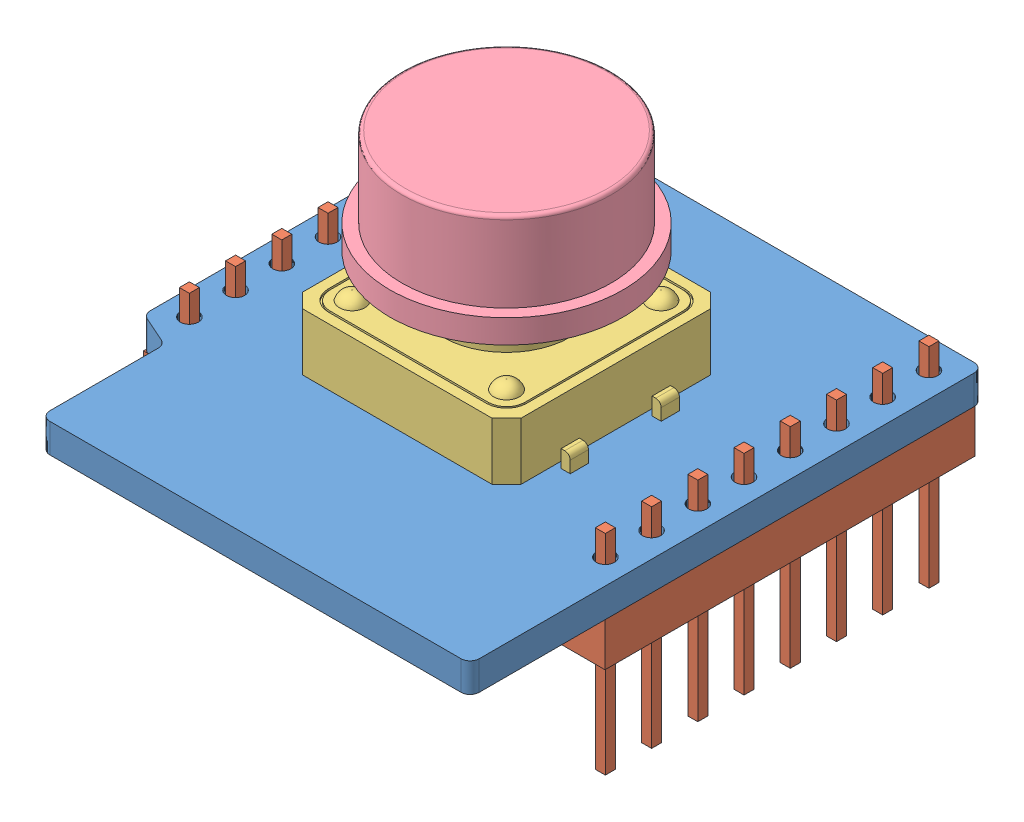
SolidWorks assembly LOLIN 1-button shield, configuration Default. Lengths in mm.
Overall size (25.6 21.7 28.2).
5 component instances, 4 part files, 12 mates.
Components (placement in the parent):
- LOLIN template-1: LOLIN template [Default] at origin size (25.6 1.6 28.2)
- header_m8-1: header_m8 [Default] at (-11.43 -2.5 -27.85) x (0 0 1) z (-1 0 0) size (20.32 11.5 2.5)
- header_m8-2: header_m8 [Default] at (11.43 -2.5 -27.85) x (0 0 1) z (-1 0 0) size (20.32 11.5 2.5)
- Tactile Push Button B3F-405 12X12x7.3mm-1: Tactile Push Button B3F-405 12X12x7.3mm [По умолчанию] at (0 1.95 -14.8) size (13 10.05 12)
- Tactile Button Caps for B3F-4055 12X12X7.3MM - Blue-1: Tactile Button Caps for B3F-4055 12X12X7.3MM - Blue [По умолчанию] at (0 13.2 -14.8) x (-1 0 0) z (0 0 1) size (12.8 7.6 12.8)
Mates (geometry in assembly coordinates):
- Coincident10: coincident anti-aligned: plane of LOLIN template-1 through (0 0 0) normal (0 -1 0); plane of header_m8-1 through (-12.68 0 -27.85) normal (0 1 0)
- Coincident3: coincident anti-aligned: plane of breakout_template-1 through (0 0 0) normal (0 -1 0); plane of header_m8-2 through (10.18 0 -27.85) normal (0 1 0)
- Parallel1: parallel anti-aligned: plane of header_m8-1 through (-11.43 -2.5 -27.85) normal (-1 0 0)
- Parallel2: parallel anti-aligned: plane of header_m8-2 through (11.43 -2.5 -27.85) normal (-1 0 0)
- Coincident5: coincident aligned: line of breakout_template-1 through (-11.43 1.6 -26.58) axis (0 -1 0); line of header_m8-1 through (-11.43 -2.5 -26.58) axis (0 -1 0)
- Coincident6: coincident aligned: line of breakout_template-1 through (11.43 1.6 -26.58) axis (0 -1 0); line of header_m8-2 through (11.43 -2.5 -26.58) axis (0 -1 0)
- Mate1: coincident anti-aligned: plane of Tactile Push Button B3F-405 12X12x7.3mm-1 through (-1.9 9 -12.9) normal (0 0 1); plane of Tactile Button Caps for B3F-4055 12X12X7.3MM - Blue-1 through (0.9124 5.6 -12.9) normal (0 0 -1)
- Mate2: coincident anti-aligned: plane of Tactile Push Button B3F-405 12X12x7.3mm-1 through (1.9 9 -12.9) normal (1 0 0); plane of Tactile Button Caps for B3F-4055 12X12X7.3MM - Blue-1 through (1.9 5.6 -12.9) normal (-1 0 0)
- Mate3: coincident anti-aligned: plane of Tactile Push Button B3F-405 12X12x7.3mm-1 through (0 5.6 -14.8) normal (0 1 0); plane of Tactile Button Caps for B3F-4055 12X12X7.3MM - Blue-1 through (0 5.6 -14.8) normal (0 -1 0)
- Coincident14: coincident anti-aligned: plane of LOLIN template-1 through (0 1.6 0) normal (0 1 0); plane of Tactile Push Button B3F-405 12X12x7.3mm-1 through (0 1.6 -14.8) normal (0 -1 0)
- Distance2: distance = 8.8 mm aligned: plane of Tactile Push Button B3F-405 12X12x7.3mm-1 through (-6 5.1 -8.8) normal (0 0 1); plane of LOLIN template-1 through (-10.8 1.6 0) normal (0 0 1)
- Coincident15: coincident aligned: plane of LOLIN template-1 through (0 0 0) normal (1 0 0); plane of Tactile Push Button B3F-405 12X12x7.3mm-1 through (0 1.95 -14.8) normal (1 0 0)
